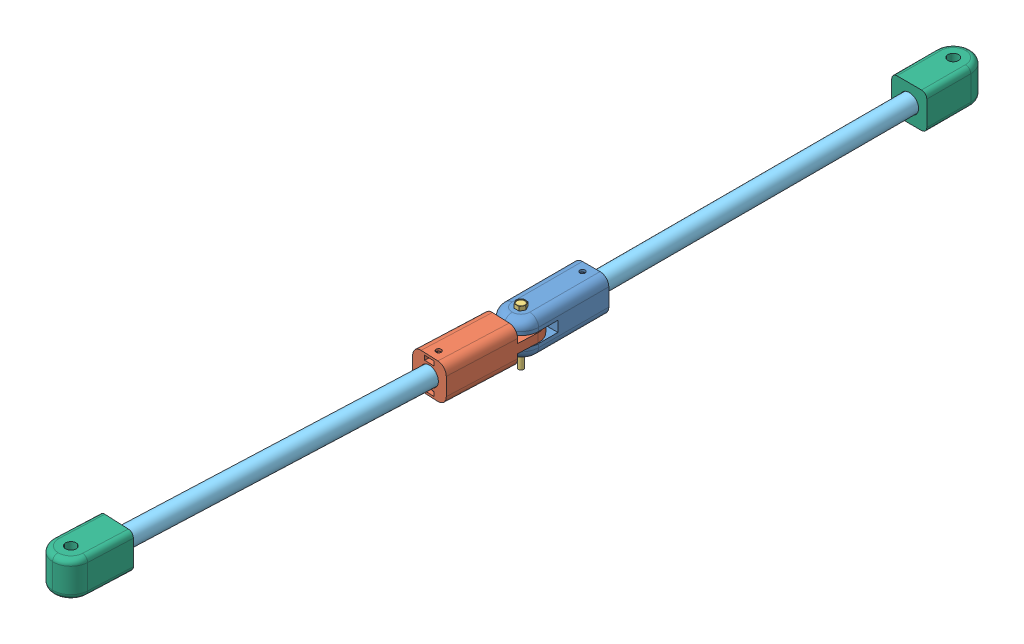
SolidWorks assembly LinkageCadAssembly, configuration Default. Lengths in mm.
Overall size (31.23 32.3 512.19).
18 component instances, 8 part files, 36 mates.
Components (placement in the parent):
- Linkage End A-1: Linkage End A [Default] at (-26.5253 8.8839 -29.1093)
- Linkage End B-1: Linkage End B [Default] at (-8.6492 8.8839 61.269) x (-0.999105 0 -0.0423) z (0.0423 0 -0.999105)
- hex screw_am-1: hex screw_am [PreviewCfg] at (-16.5253 31.1839 10.8907) x (0 -1 0) z (0 0 1)
- flat washer narrow_am-1: flat washer narrow_am [PreviewCfg] at (-16.5253 20.4839 10.8907) x (0 -1 0) z (0.94934 0 0.31425)
- flat washer narrow_am-2: flat washer narrow_am [PreviewCfg] at (-16.5253 14.9839 10.8907) x (0 -1 0) z (0.922882 0 0.385083)
- Newrod-1: Newrod [Default] at (-16.5253 18.8839 -20.1093) x (0 0 -1) z (1 0 0)
- Newrod-2: Newrod [Default] at (-26.2965 18.8839 241.684) x (0.0423 0 -0.999105) z (0.995435 -0.085632 0.042144)
- End-2: End [c] at (-16.5253 18.8839 -210.1093) x (0 0 -1) z (1 0 0)
- socket set screw cone point_am-2: socket set screw cone point_am [PreviewCfg] at (-18.4288 8.722 55.8504) x (0 1 0) z (0 0 1)
- socket set screw cone point_am-3: socket set screw cone point_am [PreviewCfg] at (-18.4288 29.0459 55.8504) x (0 -1 0) z (0.96943 0 -0.245369)
- hex nut style 1_am-2: hex nut style 1_am [PreviewCfg] at (-18.4288 12.5339 55.8504) x (1 0 0) z (0 1 0)
- hex nut style 1_am-3: hex nut style 1_am [PreviewCfg] at (-18.4288 27.6339 55.8504) x (0.999999 0 0.001242) z (0 1 0)
- hex nut style 1_am-4: hex nut style 1_am [PreviewCfg] at (-16.5253 27.5339 -24.1093) x (1 0 0) z (0 1 0)
- hex nut style 1_am-5: hex nut style 1_am [PreviewCfg] at (-16.5253 12.5339 -24.1093) x (1 0 0) z (0 1 0)
- socket set screw cone point_am-4: socket set screw cone point_am [PreviewCfg] at (-16.5253 8.722 -24.1093) x (0 1 0) z (-0.011043 0 0.999939)
- socket set screw cone point_am-5: socket set screw cone point_am [PreviewCfg] at (-16.5253 29.0459 -24.1093) x (0 -1 0) z (0.111355 0 -0.993781)
- hex nut style 1_am-6: hex nut style 1_am [PreviewCfg] at (-16.5253 8.8839 10.8907) x (0.976116 0 0.217252) z (0 1 0)
- End-3: End [c] at (-25.8735 18.8839 231.6929) x (-0.0423 0 0.999105) z (-0.999105 0 -0.0423)
Mates (geometry in assembly coordinates):
- Concentric1: concentric aligned: cylinder of Linkage End A-1 through (-16.5253 4.6413 10.8907) axis (0 1 0) radius 1.5; cylinder of Linkage End B-1 through (-16.5253 4.6413 10.8907) axis (0 1 0) radius 1.5
- Distance1: distance = 0.5 mm anti-aligned: plane of Linkage End A-1 through (-26.5253 15.8839 -0.1093) normal (0 1 0); plane of Linkage End B-1 through (-6.9995 16.3839 22.3039) normal (0 -1 0)
- Concentric21: concentric aligned: cylinder of Linkage End A-1 through (-16.5253 4.6413 10.8907) axis (0 1 0) radius 1.5; cylinder of hex screw_am-1 through (-16.5253 56.5839 10.8907) axis (0 1 0) radius 1.5
- Coincident11: coincident anti-aligned: plane of Linkage End A-1 through (-26.5253 28.8839 -4.1093) normal (0 1 0); plane of hex screw_am-1 through (-15.0253 28.8839 10.8907) normal (0 -1 0)
- Concentric3: concentric aligned: cylinder of hex screw_am-1 through (-16.5253 56.5839 10.8907) axis (0 1 0) radius 1.5; cylinder of flat washer narrow_am-1 through (-16.5253 55.4089 10.8907) axis (0 1 0) radius 2.89
- Concentric4: concentric aligned: cylinder of hex screw_am-1 through (-16.5253 56.5839 10.8907) axis (0 1 0) radius 1.5; cylinder of flat washer narrow_am-2 through (-16.5253 49.9089 10.8907) axis (0 1 0) radius 2.89
- Concentric7: concentric aligned: circle of Linkage End A-1; cylinder of Newrod-1 through (-16.5253 18.8839 -210.1093) axis (0 0 1) radius 5.1
- Concentric8: concentric aligned: cylinder of Linkage End B-1 through (-17.1598 18.8839 25.8773) axis (-0.0423 0 0.999105) radius 5.3; cylinder of Newrod-2 through (-18.2596 18.8839 51.854) axis (-0.0423 0 0.999105) radius 5.1
- Coincident5: coincident anti-aligned: plane of Newrod-1 through (-16.5253 18.8839 -210.1093) normal (0 0 -1); plane of End-2 through (-16.5253 18.8839 -210.1093) normal (0 0 1)
- Concentric10: concentric aligned: cylinder of Newrod-1 through (-16.5253 18.8839 -210.1093) axis (0 0 1) radius 5.1; cylinder of End-2 through (-16.5253 18.8839 -210.1093) axis (0 0 1) radius 5.3
- Concentric11: concentric aligned: cylinder of Linkage End B-1 through (-18.4288 4.6413 55.8504) axis (0 1 0) radius 1.5; cylinder of socket set screw cone point_am-3 through (-18.4288 41.7459 55.8504) axis (0 1 0) radius 1.5
- Coincident8: coincident aligned: plane of Linkage End B-1 through (-7.1687 28.8839 26.3003) normal (0 1 0); circle of socket set screw cone point_am-3
- Concentric14: concentric aligned: cylinder of Linkage End B-1 through (-18.4288 4.6413 55.8504) axis (0 1 0) radius 1.5; cylinder of hex nut style 1_am-2 through (-18.4288 -12.5036 55.8504) axis (0 1 0) radius 1.5
- Coincident9: coincident anti-aligned: plane of Linkage End B-1 through (-21.1243 10.1339 52.7336) normal (0 1 0); plane of hex nut style 1_am-2 through (-18.4288 10.1339 52.675) normal (0 -1 0)
- Concentric15: concentric aligned: cylinder of socket set screw cone point_am-3 through (-18.4288 41.7459 55.8504) axis (0 1 0) radius 1.5; cylinder of hex nut style 1_am-3 through (-18.4288 2.5964 55.8504) axis (0 1 0) radius 1.5
- Coincident10: coincident anti-aligned: plane of Linkage End B-1 through (-21.1243 27.6339 52.7336) normal (0 -1 0); plane of hex nut style 1_am-3 through (-18.4248 27.6339 52.675) normal (0 1 0)
- Concentric16: concentric anti-aligned: cylinder of Linkage End B-1 through (-18.4288 4.6413 55.8504) axis (0 1 0) radius 1.5; cylinder of socket set screw cone point_am-2 through (-18.4288 -3.978 55.8504) axis (0 -1 0) radius 1.5
- Coincident11: coincident aligned: plane of Linkage End B-1 through (-7.1687 8.8839 26.3003) normal (0 -1 0); circle of socket set screw cone point_am-2
- Concentric17: concentric aligned: cylinder of Linkage End A-1 through (-16.5253 4.6413 -24.1093) axis (0 1 0) radius 1.5; cylinder of hex nut style 1_am-4 through (-16.5253 2.4964 -24.1093) axis (0 1 0) radius 1.5
- Coincident12: coincident anti-aligned: plane of Linkage End A-1 through (-13.7003 25.1339 -21.1093) normal (0 1 0); plane of hex nut style 1_am-4 through (-16.5253 25.1339 -27.2847) normal (0 -1 0)
- Concentric18: concentric aligned: cylinder of Linkage End A-1 through (-16.5253 4.6413 -24.1093) axis (0 1 0) radius 1.5; cylinder of hex nut style 1_am-5 through (-16.5253 -12.5036 -24.1093) axis (0 1 0) radius 1.5
- Coincident13: coincident anti-aligned: plane of Linkage End A-1 through (-13.7003 10.1339 -21.1093) normal (0 1 0); plane of hex nut style 1_am-5 through (-16.5253 10.1339 -27.2847) normal (0 -1 0)
- Concentric20: concentric aligned: cylinder of Linkage End A-1 through (-16.5253 4.6413 -24.1093) axis (0 1 0) radius 1.5; cylinder of socket set screw cone point_am-5 through (-16.5253 41.7459 -24.1093) axis (0 1 0) radius 1.5
- Coincident14: coincident aligned: plane of Linkage End A-1 through (-26.5253 28.8839 -4.1093) normal (0 1 0); circle of socket set screw cone point_am-5
- Concentric21: concentric anti-aligned: cylinder of Linkage End A-1 through (-16.5253 4.6413 -24.1093) axis (0 1 0) radius 1.5; cylinder of socket set screw cone point_am-4 through (-16.5253 -3.978 -24.1093) axis (0 -1 0) radius 1.5
- Coincident15: coincident aligned: plane of Linkage End A-1 through (-26.5253 8.8839 -4.1093) normal (0 -1 0); circle of socket set screw cone point_am-4
- Distance4: distance = 181 mm anti-aligned: plane of End-2 through (-16.5253 18.8839 -210.1093) normal (0 0 1); plane of Linkage End A-1 through (-26.5253 8.8839 -29.1093) normal (0 0 -1)
- Coincident17: coincident aligned: plane of Linkage End A-1 through (-26.5253 8.8839 -4.1093) normal (-1 0 0); plane of End-2 through (-26.5253 8.8839 -210.1093) normal (-1 0 0)
- Coincident19: coincident anti-aligned: plane of Linkage End B-1 through (-6.9995 16.3839 22.3039) normal (0 -1 0); plane of flat washer narrow_am-2 through (-14.4073 16.3839 5.8149) normal (0 1 0)
- Coincident20: coincident anti-aligned: plane of Linkage End A-1 through (-26.5253 21.8839 -0.1093) normal (0 -1 0); plane of flat washer narrow_am-1 through (-14.7969 21.8839 5.6693) normal (0 1 0)
- Concentric22: concentric aligned: cylinder of hex screw_am-1 through (-16.5253 56.5839 10.8907) axis (0 1 0) radius 1.5; cylinder of hex nut style 1_am-6 through (-16.5253 -16.1536 10.8907) axis (0 1 0) radius 1.5
- Coincident21: coincident anti-aligned: plane of Linkage End A-1 through (-26.5253 8.8839 -4.1093) normal (0 -1 0); plane of hex nut style 1_am-6 through (-15.8354 8.8839 7.7911) normal (0 1 0)
- Coincident22: coincident anti-aligned: plane of Newrod-2 through (-26.7195 18.8839 251.675) normal (-0.0423 0 0.999105); plane of End-3 through (-26.7195 18.8839 251.675) normal (0.0423 0 -0.999105)
- Concentric23: concentric anti-aligned: cylinder of Newrod-2 through (-18.2596 18.8839 51.854) axis (-0.0423 0 0.999105) radius 5.1; cylinder of End-3 through (-26.7195 18.8839 251.675) axis (0.0423 0 -0.999105) radius 5.3
- Parallel1: parallel aligned: plane of Linkage End B-1 through (-7.1687 8.8839 26.3003) normal (0.999105 0 0.0423); plane of End-3 through (-16.7284 8.8839 252.098) normal (0.999105 0 0.0423)
- Distance5: distance = 171 mm anti-aligned: plane of End-3 through (-25.8735 18.8839 231.6929) normal (0.0423 0 -0.999105); plane of Linkage End B-1 through (-8.6492 8.8839 61.269) normal (-0.0423 0 0.999105)
